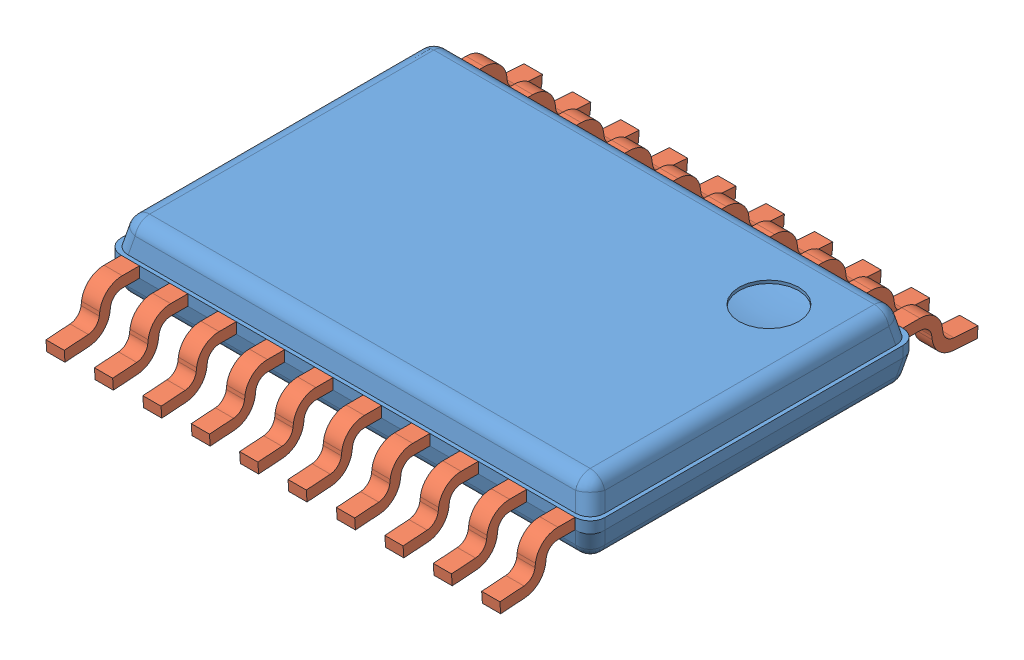
SolidWorks assembly PW0020A, configuration Default. Lengths in mm.
Overall size (6.5 1.03 6.42).
21 component instances, 2 part files, 0 mates.
Components (placement in the parent):
- BODY_MTC20-1: BODY_MTC20 [Default] at origin size (6.5 0.95 4.4)
- LEAD_MTC20-1: LEAD_MTC20 [Default] at (2.925 -0.3725 -2.6) x (-1 0 0) z (0 0 -1) size (0.25 0.62 1.01)
- LEAD_MTC20-2: LEAD_MTC20 [Default] at (2.275 -0.3725 -2.6) x (-1 0 0) z (0 0 -1) size (0.25 0.62 1.01)
- LEAD_MTC20-3: LEAD_MTC20 [Default] at (1.625 -0.3725 -2.6) x (-1 0 0) z (0 0 -1) size (0.25 0.62 1.01)
- LEAD_MTC20-4: LEAD_MTC20 [Default] at (0.975 -0.3725 -2.6) x (-1 0 0) z (0 0 -1) size (0.25 0.62 1.01)
- LEAD_MTC20-5: LEAD_MTC20 [Default] at (0.325 -0.3725 -2.6) x (-1 0 0) z (0 0 -1) size (0.25 0.62 1.01)
- LEAD_MTC20-6: LEAD_MTC20 [Default] at (-0.325 -0.3725 -2.6) x (-1 0 0) z (0 0 -1) size (0.25 0.62 1.01)
- LEAD_MTC20-7: LEAD_MTC20 [Default] at (-0.975 -0.3725 -2.6) x (-1 0 0) z (0 0 -1) size (0.25 0.62 1.01)
- LEAD_MTC20-8: LEAD_MTC20 [Default] at (-1.625 -0.3725 -2.6) x (-1 0 0) z (0 0 -1) size (0.25 0.62 1.01)
- LEAD_MTC20-9: LEAD_MTC20 [Default] at (-2.275 -0.3725 -2.6) x (-1 0 0) z (0 0 -1) size (0.25 0.62 1.01)
- LEAD_MTC20-10: LEAD_MTC20 [Default] at (-2.925 -0.3725 -2.6) x (-1 0 0) z (0 0 -1) size (0.25 0.62 1.01)
- LEAD_MTC20-11: LEAD_MTC20 [Default] at (2.925 -0.3725 2.6) size (0.25 0.62 1.01)
- LEAD_MTC20-12: LEAD_MTC20 [Default] at (2.275 -0.3725 2.6) size (0.25 0.62 1.01)
- LEAD_MTC20-13: LEAD_MTC20 [Default] at (1.625 -0.3725 2.6) size (0.25 0.62 1.01)
- LEAD_MTC20-14: LEAD_MTC20 [Default] at (0.975 -0.3725 2.6) size (0.25 0.62 1.01)
- LEAD_MTC20-15: LEAD_MTC20 [Default] at (0.325 -0.3725 2.6) size (0.25 0.62 1.01)
- LEAD_MTC20-16: LEAD_MTC20 [Default] at (-0.325 -0.3725 2.6) size (0.25 0.62 1.01)
- LEAD_MTC20-17: LEAD_MTC20 [Default] at (-0.975 -0.3725 2.6) size (0.25 0.62 1.01)
- LEAD_MTC20-18: LEAD_MTC20 [Default] at (-1.625 -0.3725 2.6) size (0.25 0.62 1.01)
- LEAD_MTC20-19: LEAD_MTC20 [Default] at (-2.275 -0.3725 2.6) size (0.25 0.62 1.01)
- LEAD_MTC20-20: LEAD_MTC20 [Default] at (-2.925 -0.3725 2.6) size (0.25 0.62 1.01)
